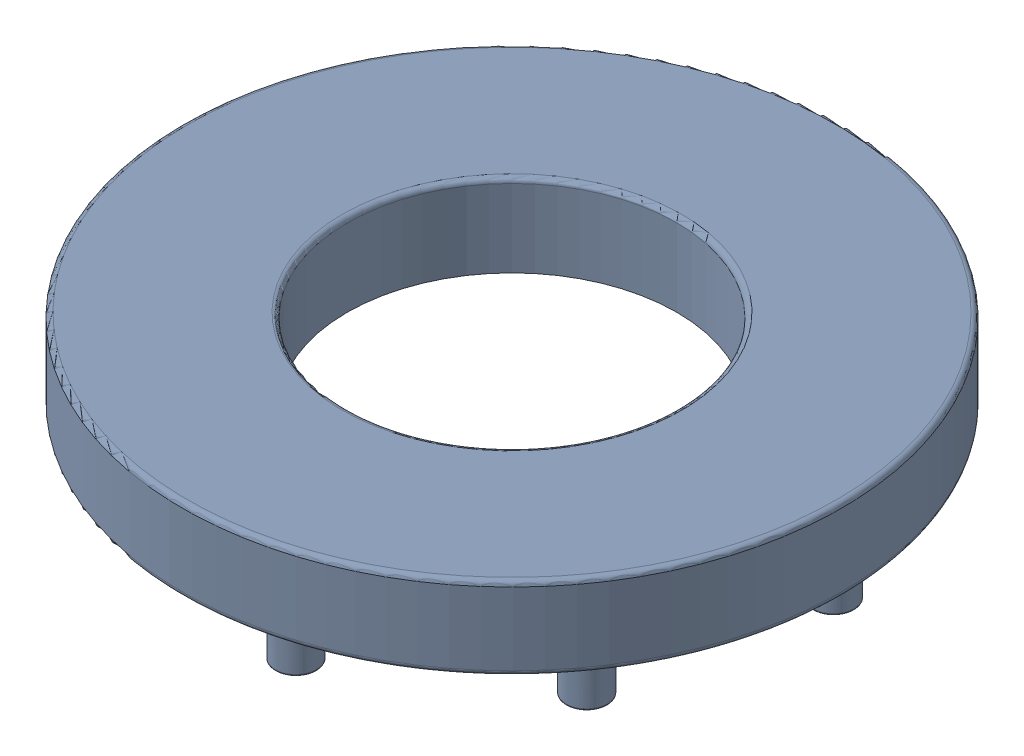
SolidWorks assembly Assembly Not Working Copy, configuration Default. Lengths in mm.
Overall size (4703.5 850 4703.5).
2 component instances, 2 part files, 4 mates.
Components (placement in the parent):
- Rotating Table-1: Rotating Table [Default] at (0 350 0) x (-0.195088 0 0.980786) z (-0.980786 0 -0.195088) size (4000 850 4000)
- Driving Shaft-1: Driving Shaft [Default] at (0 -192.8967 1882.3827) x (1 0 0) z (0 0.60679 0.794862) (suppressed, hidden)
Mates (geometry in assembly coordinates):
- Concentric3: concentric aligned: circle of Rotating Table-1
- Coincident1: coincident anti-aligned: plane of Rotating Table-1 through (-929.4362 0 1382.7908) normal (0 -1 0)
- Concentric4: concentric aligned: cylinder of Driving Shaft-1 through (-1680.0377 -200 1873) axis (1 0 0) radius 140
- Coincident3: coincident aligned: plane of Driving Shaft-1 through (0 -208.7062 1880.9179) normal (1 0 0)
